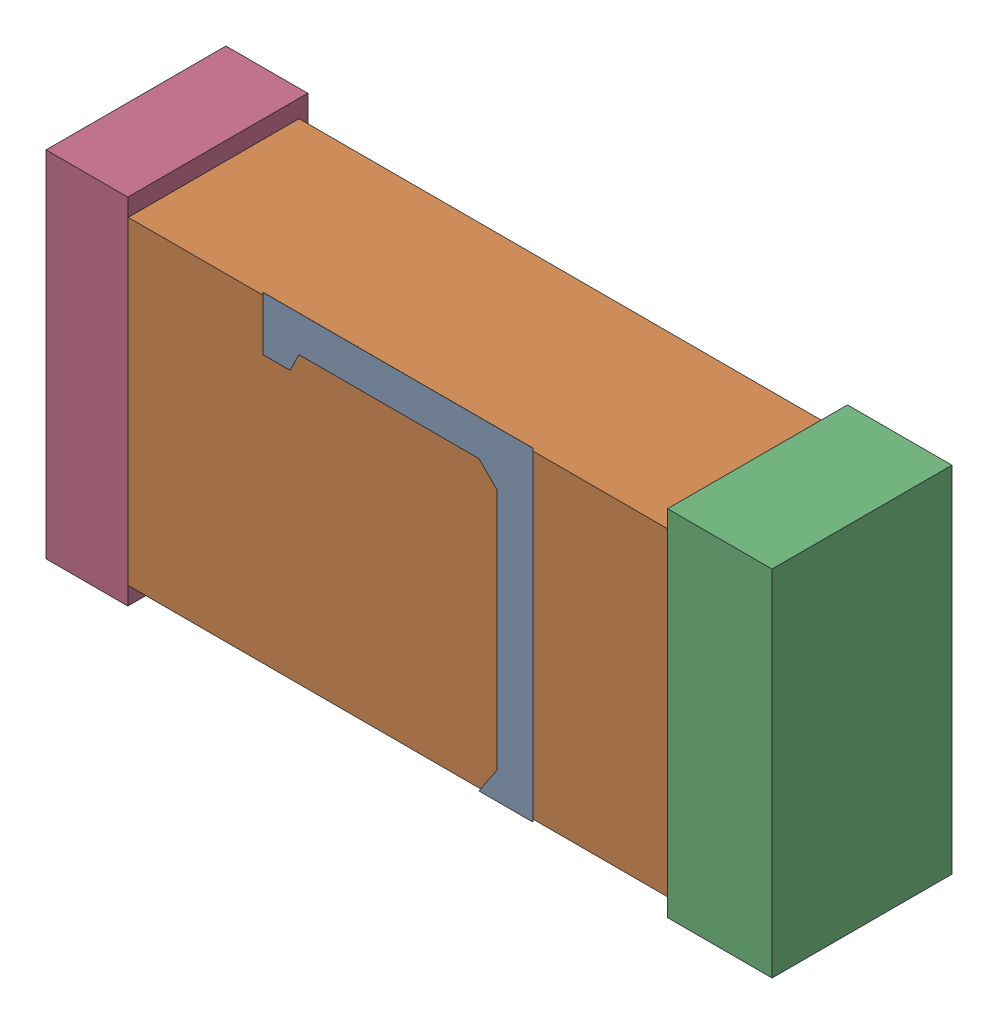
SolidWorks assembly L2, configuration Default. Lengths in mm.
Overall size (2.05 1 0.51).
12 component instances, 5 part files, 0 mates.
Components (placement in the parent):
- 710422416-1: 710422416 [Default] at (46.722 10.4866 0.508) size (0.76 0.91 0)
  - Extruded (30)-1: Extruded (30) [Default] at origin size (0.76 0.91 0)
- 710422544-1: 710422544 [Default] at (46.754 10.4866 0.0254) size (1.75 0.9 0.48)
  - Extruded (31)-1: Extruded (31) [Default] at origin size (1.75 0.9 0.48)
- 710422672-1: 710422672 [Default] at (47.6315 10.4866 0.001) size (0.29 1 0.51)
  - Extruded (32)-1: Extruded (32) [Default] at origin size (0.29 1 0.51)
- 710422800-1: 710422800 [Default] at (45.8445 10.4866 0.001) size (0.23 1 0.51)
  - Extruded (33)-1: Extruded (33) [Default] at origin size (0.23 1 0.51)
- 432120464_26-1: 432120464_26 [Default] at (47.3793 10.4866 0.001) size (0.28 0.85 0.46)
  - Extruded (11)-1: Extruded (11) [Default] at origin size (0.28 0.85 0.46)
- 432120464_27-1: 432120464_27 [Default] at (46.1551 10.4866 0.001) size (0.28 0.85 0.46)
  - Extruded (11)-1: Extruded (11) [Default] at origin size (0.28 0.85 0.46)
